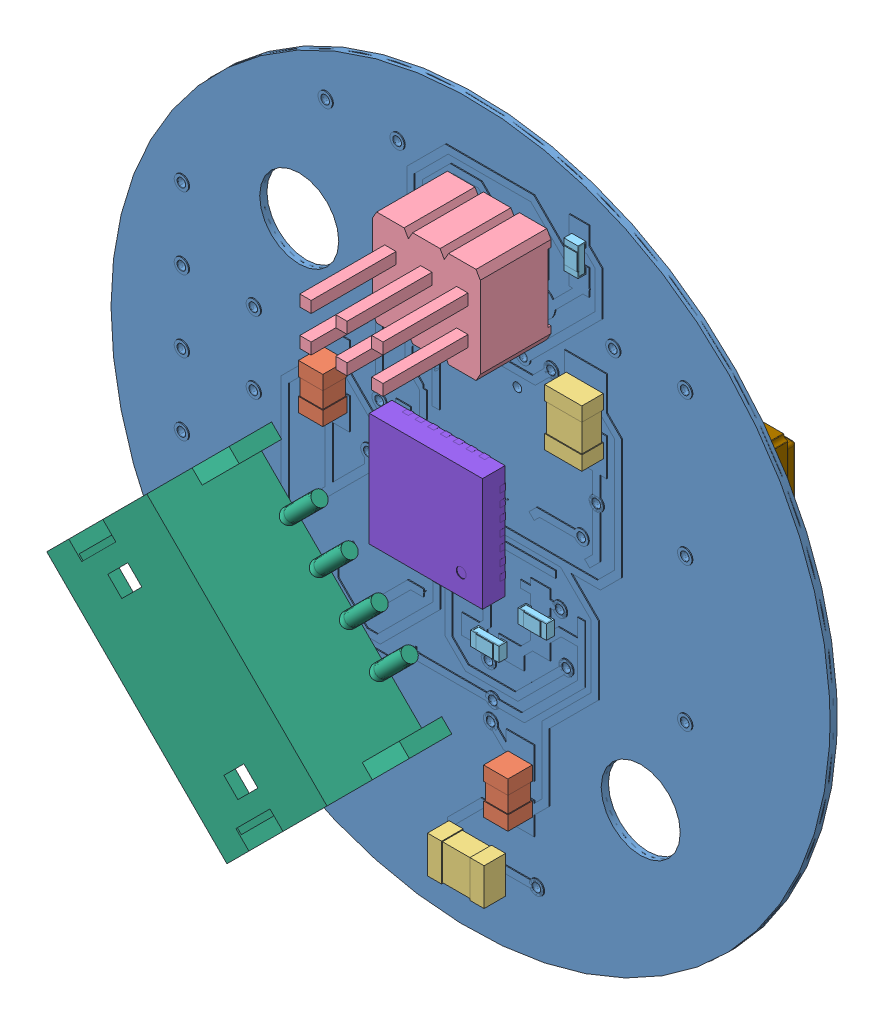
SolidWorks assembly pcb_encoder, configuration Default. Lengths in mm.
Overall size (26.72 26.87 7.85).
41 component instances, 11 part files, 0 mates.
Components (placement in the parent):
- Dip_encoder-1: Dip_encoder [Default] at origin size (26.72 26.87 0.33)
- Capacitor 0603_encoder-1: Capacitor 0603_encoder [Default] at (-4.7345 1.7721 0.352) x (0 -1 0) z (-1 0 0) size (1.6 0.86 0.86)
- Capacitor 0603_encoder-2: Capacitor 0603_encoder [Default] at (1.8045 -7.3354 0.352) x (0 -1 0) z (-1 0 0) size (1.6 0.86 0.86)
- Capacitor 0805_encoder-1: Capacitor 0805_encoder [Default] at (4.0892 5.0823 0.352) x (0 1 0) z (1 0 0) size (2 0.76 1.31)
- Capacitor 0805_encoder-2: Capacitor 0805_encoder [Default] at (0.293 -10.3648 0.352) x (-1 0 0) z (0 1 0) size (2 0.76 1.31)
- Hole_Hole_encoder-1: Hole_Hole_encoder [Default] at (6.032 -6.032 0.322)
- Hole_Hole_encoder-2: Hole_Hole_encoder [Default] at (-6.032 6.032 0.322)
- ISP_Header_encoder-1: ISP_Header_encoder [Default] at (2.2632 8.433 0.322) x (-1 0 0) z (0 1 0) size (3.81 7.85 3.4)
- res0402-1_encoder-1: res0402-1_encoder [По умолчанию] at (3.8945 9.9406 0.335) x (0 1 0) z (0 0 1) size (1 0.5 0.3)
- res0402-1_encoder-2: res0402-1_encoder [По умолчанию] at (0.838 -3.465 0.322) size (1 0.5 0.3)
- res0402-1_encoder-3: res0402-1_encoder [По умолчанию] at (2.515 -1.945 0.322) size (1 0.5 0.3)
- res0402-1_encoder-4: res0402-1_encoder [По умолчанию] at (0.457 -10.099 0) x (-1 0 0) z (0 0 -1) size (1 0.5 0.3)
- res0402-1_encoder-5: res0402-1_encoder [По умолчанию] at (0.457 -9.184 0) x (-1 0 0) z (0 0 -1) size (1 0.5 0.3)
- Static_Via_Static_Via_encoder-1: Static_Via_Static_Via_encoder [Default] at (-7.62 2.54 0.322)
- Static_Via_Static_Via_encoder-2: Static_Via_Static_Via_encoder [Default] at (-7.62 0 0.322)
- Static_Via_Static_Via_encoder-3: Static_Via_Static_Via_encoder [Default] at (-10.16 5.08 0.322)
- Static_Via_Static_Via_encoder-4: Static_Via_Static_Via_encoder [Default] at (7.62 -2.54 0.322)
- Static_Via_Static_Via_encoder-5: Static_Via_Static_Via_encoder [Default] at (5.08 7.62 0.322)
- Static_Via_Static_Via_encoder-6: Static_Via_Static_Via_encoder [Default] at (10.16 2.54 0.322)
- Static_Via_Static_Via_encoder-7: Static_Via_Static_Via_encoder [Default] at (10.16 -2.54 0.322)
- Static_Via_Static_Via_encoder-8: Static_Via_Static_Via_encoder [Default] at (-7.62 -7.62 0.322)
- Static_Via_Static_Via_encoder-9: Static_Via_Static_Via_encoder [Default] at (-2.54 -10.16 0.322)
- Static_Via_Static_Via_encoder-10: Static_Via_Static_Via_encoder [Default] at (-5.08 -7.62 0.322)
- Static_Via_Static_Via_encoder-11: Static_Via_Static_Via_encoder [Default] at (-7.62 -5.08 0.322)
- Static_Via_Static_Via_encoder-12: Static_Via_Static_Via_encoder [Default] at (-10.16 -2.54 0.322)
- Static_Via_Static_Via_encoder-13: Static_Via_Static_Via_encoder [Default] at (-10.16 0 0.322)
- Static_Via_Static_Via_encoder-14: Static_Via_Static_Via_encoder [Default] at (-10.16 2.54 0.322)
- Static_Via_Static_Via_encoder-15: Static_Via_Static_Via_encoder [Default] at (5.08 -10.16 0.322)
- Static_Via_Static_Via_encoder-16: Static_Via_Static_Via_encoder [Default] at (7.62 2.54 0.322)
- Static_Via_Static_Via_encoder-17: Static_Via_Static_Via_encoder [Default] at (7.62 7.62 0.322)
- Static_Via_Static_Via_encoder-18: Static_Via_Static_Via_encoder [Default] at (10.16 5.08 0.322)
- Static_Via_Static_Via_encoder-19: Static_Via_Static_Via_encoder [Default] at (10.16 0 0.322)
- Static_Via_Static_Via_encoder-20: Static_Via_Static_Via_encoder [Default] at (10.16 -5.08 0.322)
- Static_Via_Static_Via_encoder-21: Static_Via_Static_Via_encoder [Default] at (-5.08 -10.16 0.322)
- Static_Via_Static_Via_encoder-22: Static_Via_Static_Via_encoder [Default] at (-10.16 -5.08 0.322)
- Static_Via_Static_Via_encoder-23: Static_Via_Static_Via_encoder [Default] at (-5.08 10.16 0.322)
- Static_Via_Static_Via_encoder-24: Static_Via_Static_Via_encoder [Default] at (-2.54 10.16 0.322)
- S4B-ZR-SM4A-TF_encoder-1: S4B-ZR-SM4A-TF_encoder [Default] at (-3.7914 -3.8279 0.322) x (0.707107 -0.707107 0) z (-0.707107 -0.707107 0) size (9 3.7 6.5)
- tssop14-2_encoder-1: tssop14-2_encoder [По умолчанию] at (-0.0271 0.0569 0) x (0 1 0) z (0 0 -1) size (6.4 5.1 1.2)
- ATmega 168_encoder-1: ATmega 168_encoder [Default] at (-0.724 0.144 0.322) x (1 0 0) z (0 -1 0) size (4 0.82 4)
- GeyerElectronics_KX14_encoder-1: GeyerElectronics_KX14_encoder [По умолчанию] at (7.493 2.515 0) x (0 -1 0) z (1 0 0) size (8 1.62 4.5)
